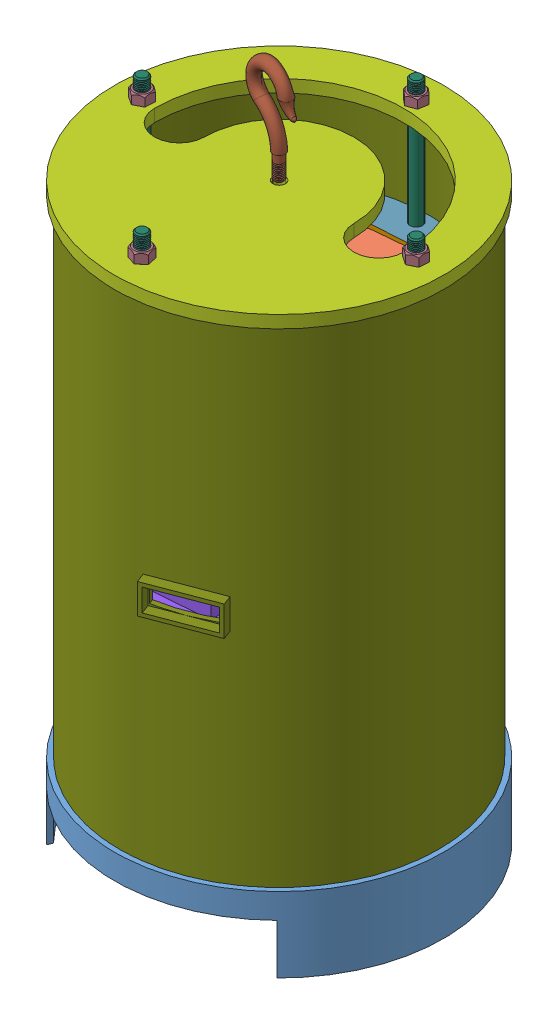
SolidWorks assembly Cansat, configuration Default. Lengths in mm.
Overall size (83.27 135.3 84.43).
24 component instances, 16 part files, 35 mates.
Components (placement in the parent):
- Base-2: Base [Default] at (23.4108 17.9988 57.3834) size (66 15 66)
- Antenna (GPS)-2: Antenna (GPS) [Default] at (30.0714 112.2022 46.6837) x (0.996195 0 -0.087156) z (0.087156 0 0.996195) size (15 4 15)
- Antenna (RF)-2: Antenna (RF) [Default] at (9.0622 114.4522 75.2659) x (-0.043619 0 -0.999048) z (0.999048 0 -0.043619) size (6 6.93 10.5)
- Arduino nano-2: Arduino nano [Default] at (32.1803 60.1363 58.2) x (-0.078459 0 -0.996917) z (0.996917 0 -0.078459) size (47.5 6 18)
- Battery-1: Battery [Default] at (9.4042 30.4988 65.2261) size (48 15 25)
- BMP-1: BMP [Default] at (13.6843 59.1363 40.6308) size (10 2 13)
- Cover-1: Cover [Default] at (23.4108 130.725 57.3834) size (66 2.5 66)
- DHT11-1: DHT11 [Default] at (13.7282 60.1363 65.3313) x (0.996917 0 -0.078459) z (0.078459 0 0.996917) size (19 6.5 29)
- GPS-1: GPS [Default] at (31.117 112.2022 45.1384) x (-0.998135 0 0.061049) z (-0.061049 0 -0.998135) size (30 2.5 20)
- HC-12 (RF)-1: HC-12 (RF) [Default] at (28.385 113.2022 71.6201) x (-0.99863 0 0.052336) z (-0.052336 0 -0.99863) size (27.8 3 14.4)
- Hook-1: Hook [Default] at (27.1573 141.8384 57.9698) x (0.987972 0 0.15463) z (0 1 0) size (11.16 2.66 19.96)
- MPU-1: MPU [Default] at (21.9564 86.6691 55.8028) size (20.3 2 15.6)
- Nut-1: Nut [Default] at (-4.0892 135.5545 57.3834) x (0.998207 0 0.059858) z (-0.059858 0 0.998207) size (3.5 2 4.44)
- Nut-2: Nut [Default] at (23.4108 135.6141 84.8834) x (0.978775 0 -0.204935) z (0.204935 0 0.978775) size (3.5 2 4.44)
- Nut-3: Nut [Default] at (50.9108 135.2538 57.3834) x (0.997746 0 0.067106) z (-0.067106 0 0.997746) size (3.5 2 4.44)
- Nut-4: Nut [Default] at (23.4108 135.1712 29.8834) x (0.63757 0 -0.770392) z (0.770392 0 0.63757) size (3.5 2 4.44)
- PCB-2: PCB [Default] at (23.4108 83.6691 57.3834) x (0 0 1) z (-1 0 0) size (60 3 60)
- PCB-3: PCB [Default] at (23.4108 56.1363 57.3834) x (0 0 1) z (-1 0 0) size (60 3 60)
- PCB-4: PCB [Default] at (23.4108 109.2022 57.3834) x (0 0 1) z (-1 0 0) size (60 3 60)
- Rod-1: Rod [Default] at (23.4108 28.3245 84.8834) x (0.51847 0 -0.855096) z (0.855096 0 0.51847) size (5 111.5 5)
- Rod-2: Rod [Default] at (50.9108 27.4561 57.3834) x (-0.908631 0 0.4176) z (-0.4176 0 -0.908631) size (5 111.5 5)
- Rod-5: Rod [Default] at (23.4108 27.4692 29.8834) x (-0.966748 0 -0.255729) z (0.255729 0 -0.966748) size (5 111.5 5)
- Rod-6: Rod [Default] at (-4.0892 27.8938 57.3834) x (-0.160074 0 -0.987105) z (0.987105 0 -0.160074) size (5 111.5 5)
- Body-2: Body [Default] at (23.4108 30.4988 57.3834) x (0.934829 0 -0.3551) z (0.3551 0 0.934829) size (64 100 66)
Mates (geometry in assembly coordinates):
- Coincident1: coincident anti-aligned: plane of Base-2 through (23.4108 30.4988 57.3834) normal (0 1 0); plane of Battery-1 through (9.4042 30.4988 65.2261) normal (0 -1 0)
- Concentric1: concentric aligned: cylinder of PCB-4 through (23.4108 112.2022 84.8834) axis (0 -1 0) radius 1.25; cylinder of Rod-1 through (23.4108 138.3245 84.8834) axis (0 -1 0) radius 1.25
- Concentric2: concentric aligned: cylinder of PCB-3 through (23.4108 59.1363 84.8834) axis (0 -1 0) radius 1.25; cylinder of Rod-1 through (23.4108 138.3245 84.8834) axis (0 -1 0) radius 1.25
- Concentric3: concentric aligned: cylinder of PCB-2 through (23.4108 86.6691 84.8834) axis (0 -1 0) radius 1.25; cylinder of Rod-1 through (23.4108 138.3245 84.8834) axis (0 -1 0) radius 1.25
- Concentric5: concentric aligned: cylinder of Base-2 through (23.4108 30.4988 84.8834) axis (0 -1 0) radius 1.25; cylinder of Rod-1 through (23.4108 138.3245 84.8834) axis (0 -1 0) radius 1.25
- Concentric6: concentric aligned: cylinder of PCB-4 through (50.9108 112.2022 57.3834) axis (0 -1 0) radius 1.25; cylinder of Rod-2 through (50.9108 137.4561 57.3834) axis (0 -1 0) radius 1.25
- Concentric7: concentric aligned: cylinder of PCB-2 through (50.9108 86.6691 57.3834) axis (0 -1 0) radius 1.25; cylinder of Rod-2 through (50.9108 137.4561 57.3834) axis (0 -1 0) radius 1.25
- Concentric8: concentric aligned: cylinder of PCB-3 through (50.9108 59.1363 57.3834) axis (0 -1 0) radius 1.25; cylinder of Rod-2 through (50.9108 137.4561 57.3834) axis (0 -1 0) radius 1.25
- Concentric10: concentric aligned: cylinder of Base-2 through (50.9108 30.4988 57.3834) axis (0 -1 0) radius 1.25; cylinder of Rod-2 through (50.9108 137.4561 57.3834) axis (0 -1 0) radius 1.25
- Coincident8: coincident anti-aligned: plane of Arduino nano-2 through (32.1803 59.1363 58.2) normal (0 -1 0); plane of PCB-3 through (23.4108 59.1363 57.3834) normal (0 1 0)
- Coincident10: coincident anti-aligned: plane of GPS-1 through (31.117 112.2022 45.1384) normal (0 -1 0); plane of PCB-4 through (23.4108 112.2022 57.3834) normal (0 1 0)
- Coincident11: coincident anti-aligned: plane of Antenna (GPS)-2 through (35.4882 112.2022 51.2289) normal (0 -1 0); plane of PCB-4 through (23.4108 112.2022 57.3834) normal (0 1 0)
- Coincident12: coincident anti-aligned: plane of HC-12 (RF)-1 through (28.385 112.2022 71.6201) normal (0 -1 0); plane of PCB-4 through (23.4108 112.2022 57.3834) normal (0 1 0)
- Coincident13: coincident anti-aligned: plane of MPU-1 through (21.9564 86.6691 55.8028) normal (0 -1 0); plane of PCB-2 through (23.4108 86.6691 57.3834) normal (0 1 0)
- Coincident14: coincident anti-aligned: plane of DHT11-1 through (13.7282 59.1363 65.3313) normal (0 -1 0); plane of PCB-3 through (23.4108 59.1363 57.3834) normal (0 1 0)
- Coincident15: coincident anti-aligned: plane of BMP-1 through (13.6843 59.1363 40.6308) normal (0 -1 0); plane of PCB-3 through (23.4108 59.1363 57.3834) normal (0 1 0)
- Tangent1: tangent: plane of assembly; face of Antenna (RF)-2; plane of PCB-4 through (23.4108 112.2022 57.3834) normal (0 1 0)
- Concentric22: concentric aligned: cylinder of PCB-4 through (-4.0892 112.2022 57.3834) axis (0 -1 0) radius 1.25; cylinder of Rod-6 through (-4.0892 137.8938 57.3834) axis (0 -1 0) radius 1.25
- Concentric23: concentric aligned: cylinder of PCB-2 through (-4.0892 86.6691 57.3834) axis (0 -1 0) radius 1.25; cylinder of Rod-6 through (-4.0892 137.8938 57.3834) axis (0 -1 0) radius 1.25
- Concentric24: concentric aligned: cylinder of PCB-3 through (-4.0892 59.1363 57.3834) axis (0 -1 0) radius 1.25; cylinder of Rod-6 through (-4.0892 137.8938 57.3834) axis (0 -1 0) radius 1.25
- Concentric25: concentric aligned: cylinder of Base-2 through (-4.0892 30.4988 57.3834) axis (0 -1 0) radius 1.25; cylinder of Rod-6 through (-4.0892 137.8938 57.3834) axis (0 -1 0) radius 1.25
- Concentric26: concentric aligned: cylinder of PCB-4 through (23.4108 112.2022 29.8834) axis (0 -1 0) radius 1.25; cylinder of Rod-5 through (23.4108 137.4692 29.8834) axis (0 -1 0) radius 1.25
- Concentric27: concentric aligned: cylinder of PCB-2 through (23.4108 86.6691 29.8834) axis (0 -1 0) radius 1.25; cylinder of Rod-5 through (23.4108 137.4692 29.8834) axis (0 -1 0) radius 1.25
- Concentric28: concentric aligned: cylinder of Base-2 through (23.4108 30.4988 29.8834) axis (0 -1 0) radius 1.25; cylinder of Rod-5 through (23.4108 137.4692 29.8834) axis (0 -1 0) radius 1.25
- Concentric31: concentric aligned: cylinder of Cover-1 through (50.9108 133.225 57.3834) axis (0 -1 0) radius 1.25; cylinder of Rod-2 through (50.9108 137.4561 57.3834) axis (0 -1 0) radius 1.25
- Concentric32: concentric aligned: cylinder of Cover-1 through (23.4108 133.225 84.8834) axis (0 -1 0) radius 1.25; cylinder of Rod-1 through (23.4108 138.3245 84.8834) axis (0 -1 0) radius 1.25
- Concentric33: concentric aligned: cylinder of Cover-1 through (-4.0892 133.225 57.3834) axis (0 -1 0) radius 1.25; cylinder of Rod-6 through (-4.0892 137.8938 57.3834) axis (0 -1 0) radius 1.25
- Concentric34: concentric aligned: cylinder of Cover-1 through (23.4108 133.225 29.8834) axis (0 -1 0) radius 1.25; cylinder of Rod-5 through (23.4108 137.4692 29.8834) axis (0 -1 0) radius 1.25
- Concentric35: concentric anti-aligned: cylinder of Cover-1 through (23.4108 133.225 57.3834) axis (0 -1 0) radius 1; cylinder of Hook-1 through (23.4108 133.341 57.3834) axis (0 1 0) radius 1
- Concentric37: concentric anti-aligned: cylinder of Nut-1 through (-4.0892 133.5545 57.3834) axis (0 1 0) radius 1.25; cylinder of Rod-6 through (-4.0892 137.8938 57.3834) axis (0 -1 0) radius 1.25
- Concentric38: concentric anti-aligned: cylinder of Nut-4 through (23.4108 133.1712 29.8834) axis (0 1 0) radius 1.25; cylinder of Rod-5 through (23.4108 137.4692 29.8834) axis (0 -1 0) radius 1.25
- Concentric39: concentric anti-aligned: cylinder of Nut-3 through (50.9108 133.2538 57.3834) axis (0 1 0) radius 1.25; cylinder of Rod-2 through (50.9108 137.4561 57.3834) axis (0 -1 0) radius 1.25
- Concentric40: concentric anti-aligned: cylinder of Nut-2 through (23.4108 133.6141 84.8834) axis (0 1 0) radius 1.25; cylinder of Rod-1 through (23.4108 138.3245 84.8834) axis (0 -1 0) radius 1.25
- Coincident33: coincident anti-aligned: plane of Base-2 through (23.4108 30.4988 57.3834) normal (0 1 0); plane of Body-2 through (23.4108 30.4988 57.3834) normal (0 -1 0)
- Concentric43: concentric anti-aligned: circle of Base-2; circle of Body-2
